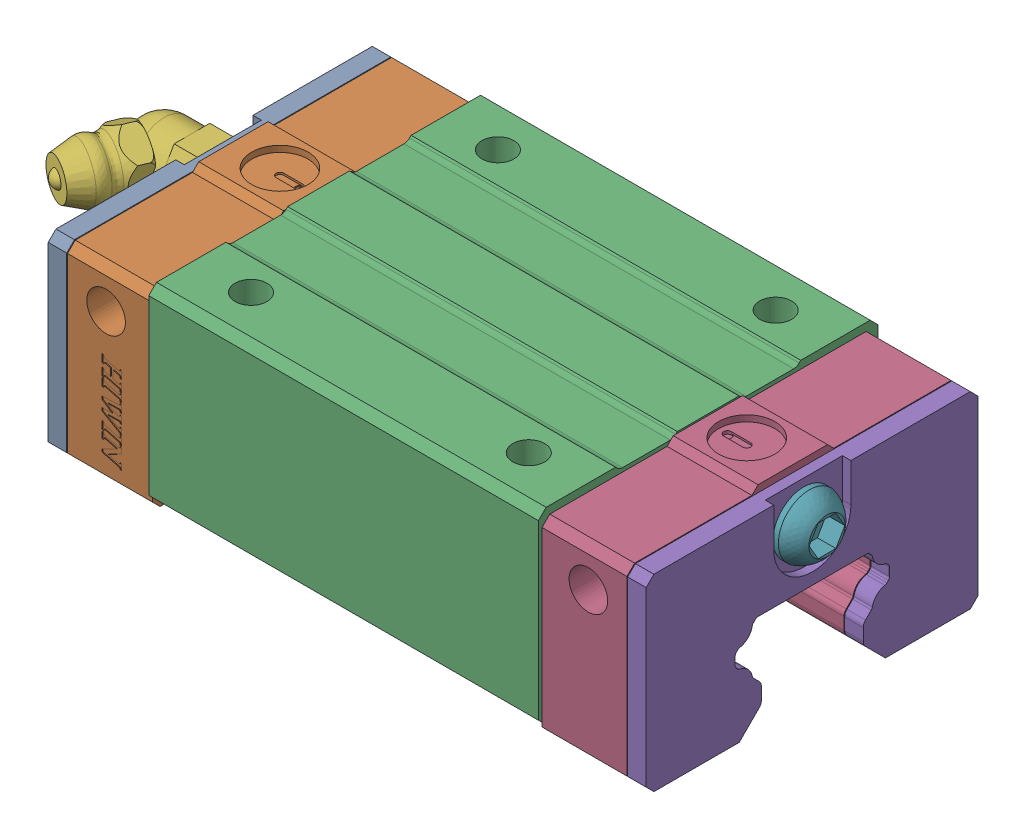
SolidWorks assembly HGR20 滑块, configuration 默认. Lengths in mm.
Overall size (97.48 36.05 44).
3 component instances, 3 part files, 4 mates.
Components (placement in the parent):
- LM滑块-1: LM滑块 [默认] at (-242 0 0) x (0 0 -1) z (1 0 0) size (44 25.4 77.5)
- 螺纹接头-1: 螺纹接头 [默认] at (-295.1321 19.3089 7.0344) x (-0.46194 0.191342 -0.866025) z (-0.745248 -0.613137 0.262049) size (15.11 19.64 23.4)
- M6H-1: M6H [默认] at (-205.2216 7.1862 0) x (0 1 0) z (1 0 0) size (8 8 8)
Mates (geometry in assembly coordinates):
- 同心1: concentric anti-aligned: circle of 复件 HGH20C_右封_temp^装配体4_HGH20CA2R600Z0C_GW202203003928_过道-1; circle of 复件 34320001^装配体4_HGH20CA2R600Z0C_GW202203003928_过道-1
- 重合10: coincident anti-aligned: plane of 复件 HGH20C_右封_temp^装配体4_HGH20CA2R600Z0C_GW202203003928_过道-1 through (-279.65 7.6798 0) normal (-1 0 0); plane of 复件 34320001^装配体4_HGH20CA2R600Z0C_GW202203003928_过道-1 through (-279.65 6.5 0) normal (1 0 0)
- 同心2: concentric anti-aligned: circle of 复件 HGH20C_右封_temp^装配体4_HGH20CA2R600Z0C_GW202203003928_过道-1; circle of 复件 M6H^装配体4_HGH20CA2R600Z0C_GW202203003928_过道-1
- 重合12: coincident anti-aligned: plane of 复件 HGH20C_右封_temp^装配体4_HGH20CA2R600Z0C_GW202203003928_过道-1 through (-204.35 7.6798 0) normal (1 0 0); plane of 复件 M6H^装配体4_HGH20CA2R600Z0C_GW202203003928_过道-1 through (-204.35 10.5 0) normal (-1 0 0)
